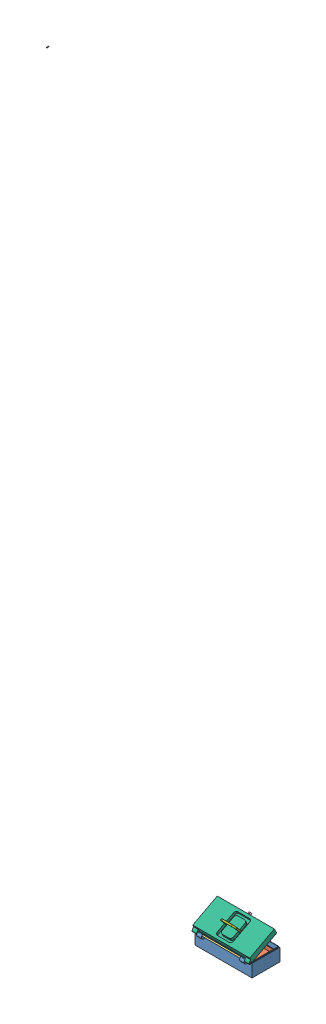
SolidWorks assembly Assem1, configuration Default. Lengths in mm.
Overall size (4398.61 1501.16 3108.46).
13 component instances, 9 part files, 27 mates.
Components (placement in the parent):
- Box (1)-1: Box (1) [Default] at origin size (374.76 95.21 200)
- tray-1: tray [Default] at (0 64 2.5) size (355 59 165)
- Rod4-1: Rod4 [Default] at (185 89 100.5) x (0 0 1) z (-1 0 0) size (8 8 370)
- Holder2 -1: Holder2  [Default] at (-10 194.5352 -59.2297) x (1 0 0) z (0 0.46573 -0.884927) size (20 20 20)
- Holder1 -1: Holder1  [Default] at (10 67.5 -90) x (-1 0 0) z (0 0 -1) size (20 20 20)
- cover2017-2: cover2017 [Default] at (185 119.553 104.7144) x (-1 0 0) z (0 -0.884927 -0.46573) size (370 198.65 35)
- handle-2: handle [Default] at (0 202.123 63.2847) x (1 0 0) z (0 -0.655971 0.754786) size (102.52 75.02 10)
- Hook (1)-1: Hook (1) [Default] at (1.8846 54.5 -130.9074) x (0.998146 0 0.060861) z (-0.060861 0 0.998146) size (10.5 50.46 35.46)
- round head rivet as-1: round head rivet as [AS B118 Round - 0.156 x 0.5] at (-4210.1434 1497.6883 -2971.5722) size (6.93 6.93 15.67)
- round head rivet as-6: round head rivet as [AS B118 Round - 0.188 x 0.375] at (-5 77.5 -93.5814) x (0.998892 -0.047067 0) z (0 0 -1) size (8.33 8.33 13.11)
- round head rivet as-7: round head rivet as [AS B118 Round - 0.188 x 0.375] at (5 77.5 -96.0814) x (-0.989693 0.143207 0) z (0 0 -1) size (8.33 8.33 13.11)
- round head rivet as-9: round head rivet as [AS B118 Round - 0.188 x 0.375] at (5 183.395 -70.2698) x (-0.883345 -0.414786 -0.218299) z (0 0.46573 -0.884927) size (8.33 8.33 13.11)
- round head rivet as-10: round head rivet as [AS B118 Round - 0.188 x 0.375] at (-5 183.395 -70.2698) x (-0.946113 0.286572 0.15082) z (0 0.46573 -0.884927) size (8.33 8.33 13.11)
Mates (geometry in assembly coordinates):
- Coincident1: coincident anti-aligned: plane of Box (1)-1 through (-185 87.5 85) normal (0 0 -1); plane of tray-1 through (0 64 85) normal (0 0 1)
- Width1: width aligned: plane of tray-1 through (177.5 64 81) normal (1 0 0); plane of Box (1)-1 through (-177.5 60 81) normal (-1 0 0); plane of tray-1 through (-180 87.5 85) normal (1 0 0); plane of Box (1)-1 through (180 80.5 85) normal (-1 0 0)
- Parallel2: parallel anti-aligned: plane of Box (1)-1 through (-185 87.5 -85) normal (0 0 1); plane of tray-1 through (0 64 -80) normal (0 0 -1)
- Coincident4: coincident anti-aligned: plane of Box (1)-1 through (0 60 0) normal (0 1 0); plane of tray-1 through (-177.5 60 81) normal (0 -1 0)
- Concentric3: concentric anti-aligned: cylinder of Rod4-1 through (-185 89 100.5) axis (1 0 0) radius 4; cylinder of cover2017-2 through (185 89 100.5) axis (-1 0 0) radius 4
- Concentric4: concentric aligned: cylinder of Box (1)-1 through (185 89 100.5) axis (-1 0 0) radius 4.1; cylinder of cover2017-2 through (185 89 100.5) axis (-1 0 0) radius 4
- Width4: width anti-aligned: plane of cover2017-2 through (-155 106.2791 97.7285) normal (1 0 0); plane of Box (1)-1 through (155 106.2791 97.7285) normal (-1 0 0); plane of cover2017-2 through (-154 0 0) normal (-1 0 0); plane of Box (1)-1 through (154 0 0) normal (1 0 0)
- Coincident6: coincident anti-aligned: plane of Rod4-1 through (185 89 100.5) normal (1 0 0); circle of cover2017-2
- Concentric6: concentric anti-aligned: cylinder of cover2017-2 through (36.5 153.0619 20.6466) axis (1 0 0) radius 2.75; cylinder of handle-2 through (30 153.0619 20.6466) axis (-1 0 0) radius 2.5
- Width6: width anti-aligned: plane of handle-2 through (-30 153.0619 20.6466) normal (1 0 0); plane of cover2017-2 through (30 153.0619 20.6466) normal (-1 0 0); plane of handle-2 through (-36.5 134.9221 75.5119) normal (-1 0 0); plane of cover2017-2 through (36.5 188.0154 -25.3698) normal (1 0 0)
- Concentric7: concentric aligned: cylinder of Box (1)-1 through (-5 77.5 -60) axis (0 0 -1) radius 2.5; cylinder of Holder1 -1 through (-5 77.5 -90) axis (0 0 -1) radius 2.5
- Coincident8: coincident anti-aligned: plane of Box (1)-1 through (-185 87.5 -90) normal (0 0 -1); plane of Holder1 -1 through (10 67.5 -90) normal (0 0 1)
- Concentric8: concentric aligned: cylinder of Box (1)-1 through (5 77.5 -60) axis (0 0 -1) radius 2.5; cylinder of Holder1 -1 through (5 77.5 -90) axis (0 0 -1) radius 2.5
- Concentric9: concentric aligned: cylinder of Holder2 -1 through (-5 181.2613 -66.2156) axis (0 0.46573 -0.884927) radius 2.5; cylinder of cover2017-2 through (-5 88.744 109.5752) axis (0 0.46573 -0.884927) radius 2.5
- Concentric10: concentric aligned: cylinder of Holder2 -1 through (5 181.2613 -66.2156) axis (0 0.46573 -0.884927) radius 2.5; cylinder of cover2017-2 through (5 88.744 109.5752) axis (0 0.46573 -0.884927) radius 2.5
- Coincident9: coincident anti-aligned: plane of Holder2 -1 through (-10 194.5352 -59.2297) normal (0 -0.46573 0.884927); plane of cover2017-2 through (-185 203.3845 -54.5724) normal (0 0.46573 -0.884927)
- Concentric12: concentric aligned: cylinder of Holder1 -1 through (0 67.5 -100) axis (0 1 0) radius 5; cylinder of Hook (1)-1 through (0 60.4648 -100) axis (0 1 0) radius 4.5
- Tangent2: tangent anti-aligned: plane of Holder1 -1 through (10 87.5 -110) normal (0 1 0); cylinder of Hook (1)-1 through (5.9867 89.5 -99.5997) axis (-0.998146 0 -0.060861) radius 2
- Coincident10: coincident anti-aligned: plane of Box (1)-1 through (-185 87.5 -90) normal (0 0 -1); plane of round head rivet as-6 through (-9.161 77.6961 -90) normal (0 0 1)
- Concentric14: concentric aligned: cylinder of Box (1)-1 through (5 77.5 -60) axis (0 0 -1) radius 2.5; cylinder of round head rivet as-7 through (5 77.5 -96.0814) axis (0 0 -1) radius 2.3876
- Coincident11: coincident anti-aligned: plane of Holder1 -1 through (10 67.5 -92.5) normal (0 0 -1); plane of round head rivet as-7 through (9.1227 76.9035 -92.5) normal (0 0 1)
- Parallel4: parallel anti-aligned: plane of Holder1 -1 through (10 67.5 -92.5) normal (0 0 -1); plane of round head rivet as-6 through (-9.161 77.6961 -90) normal (0 0 1)
- Concentric17: concentric aligned: cylinder of Holder1 -1 through (-5 77.5 -90) axis (0 0 -1) radius 2.5; cylinder of round head rivet as-6 through (-5 77.5 -93.5814) axis (0 0 -1) radius 2.3876
- Concentric18: concentric aligned: cylinder of cover2017-2 through (5 88.744 109.5752) axis (0 0.46573 -0.884927) radius 2.5; cylinder of round head rivet as-9 through (5 183.395 -70.2698) axis (0 0.46573 -0.884927) radius 2.3876
- Coincident14: coincident anti-aligned: plane of Holder2 -1 through (-10 195.0009 -60.1146) normal (0 0.46573 -0.884927); plane of round head rivet as-9 through (8.6797 183.4548 -66.1912) normal (0 -0.46573 0.884927)
- Concentric19: concentric aligned: cylinder of Holder2 -1 through (-5 181.2613 -66.2156) axis (0 0.46573 -0.884927) radius 2.5; cylinder of round head rivet as-10 through (-5 183.395 -70.2698) axis (0 0.46573 -0.884927) radius 2.3876
- Coincident15: coincident anti-aligned: plane of Holder2 -1 through (-10 195.0009 -60.1146) normal (0 0.46573 -0.884927); plane of round head rivet as-10 through (-1.0589 180.5333 -67.7288) normal (0 -0.46573 0.884927)
